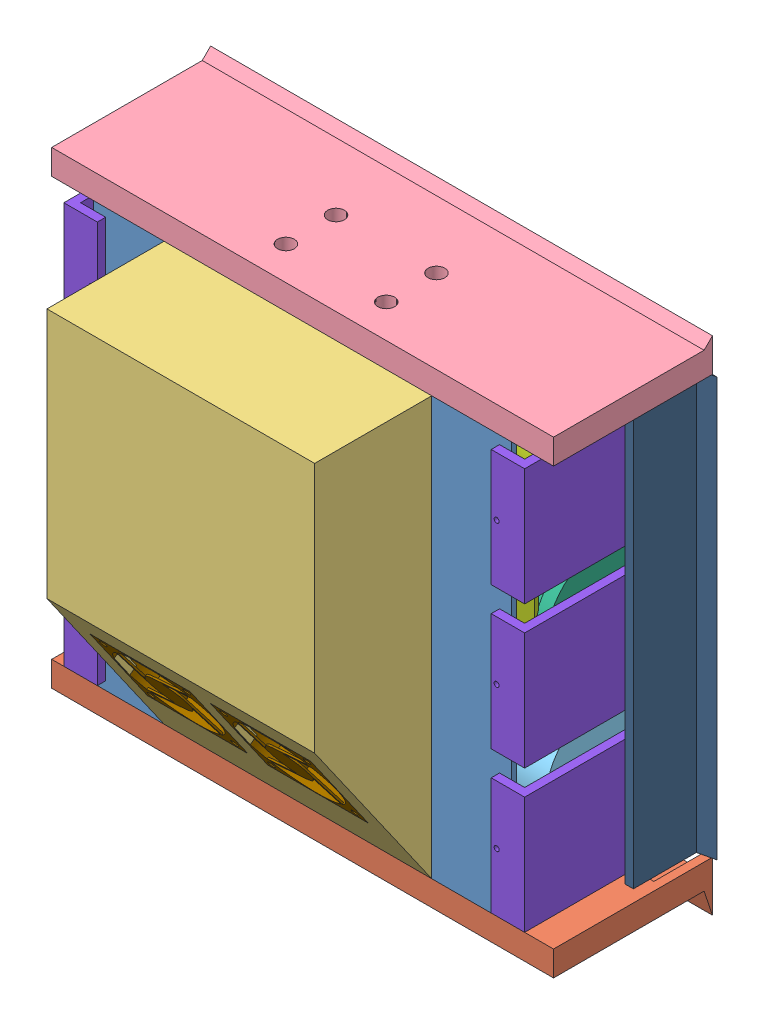
SolidWorks assembly Assemblage2, configuration Défaut. Lengths in mm.
Overall size (305.46 300 182.57).
24 component instances, 10 part files, 62 mates.
Components (placement in the parent):
- Pièce1-1: Pièce1 [Défaut] at (-19.0558 93.3364 250.0001) size (250 250 96)
- avant-1: avant [Défaut] at (151.0087 -127.6434 251.0001) x (-1 0 0) z (0 1 0) size (300 95 30)
- chassis sup-1: chassis sup [Défaut] at (-76.8076 137.3566 346.0001) x (0 1 0) z (1 0 0) size (250 70 160)
- arriere-1: arriere [Défaut] at (-148.9913 152.3566 251.0001) x (1 0 0) z (0 -1 0) size (300 95 20)
- roues 70x60-1: roues 70x60 [Défaut] at (116.0087 92.3566 280.5001) x (0 0.924225 0.381849) z (-1 0 0) size (70 70 60)
- roues 70x60-2: roues 70x60 [Défaut] at (56.0087 -67.6434 280.5001) x (0 0 -1) z (1 0 0) size (70 70 60)
- roues 70x60-3: roues 70x60 [Défaut] at (-53.9913 -67.6434 280.5001) x (0 0 1) z (-1 0 0) size (70 70 60)
- roues 70x60-4: roues 70x60 [Défaut] at (-113.9913 92.3566 280.5001) x (0 0 -1) z (1 0 0) size (70 70 60)
- roues moteur-1: roues moteur [Défaut] at (56.0087 12.3566 280.5001) x (0 0.453497 -0.891258) z (1 0 0) size (70 70 60)
- roues moteur-2: roues moteur [Défaut] at (-53.9913 12.3566 280.5001) x (0 -0.924225 -0.381849) z (-1 0 0) size (70 70 60)
- courroie-1: courroie [Défaut] at (89.0087 12.3566 280.5001) x (0 1 0) z (1 0 0) size (150 70 20)
- courroie-2: courroie [Défaut] at (63.0087 12.3566 280.5001) x (0 -1 0) z (1 0 0) size (150 70 20)
- courroie-3: courroie [Défaut] at (-80.9913 12.3566 280.5001) x (0 -1 0) z (1 0 0) size (150 70 20)
- courroie-4: courroie [Défaut] at (-106.4913 92.3566 280.5001) x (0 -1 0) z (1 0 0) size (150 70 20)
- Pièce6-2: Pièce6 [Défaut] at (118.7412 -37.6434 351.0001) x (0 1 0) z (0 0 -1) size (70 20 75)
- Pièce6-3: Pièce6 [Défaut] at (118.7412 47.3566 351.0001) x (0 1 0) z (0 0 -1) size (70 20 75)
- Pièce6-4: Pièce6 [Défaut] at (118.7412 132.3566 351.0001) x (0 1 0) z (0 0 -1) size (70 20 75)
- Pièce6-5: Pièce6 [Défaut] at (-116.7237 -107.6434 351.0001) x (0 -1 0) z (0 0 -1) size (70 20 75)
- Pièce6-6: Pièce6 [Défaut] at (-116.7237 -22.6434 351.0001) x (0 -1 0) z (0 0 -1) size (70 20 75)
- Pièce6-7: Pièce6 [Défaut] at (-116.7237 62.3566 351.0001) x (0 -1 0) z (0 0 -1) size (70 20 75)
- VENTILATEUR SUNON 60x60x25-1: VENTILATEUR SUNON 60x60x25 [Défaut] at (-38.8076 -55.2972 386.1425) x (1 0 0) z (0 -0.573462 0.819232) size (60 60 25)
- VENTILATEUR SUNON 60x60x25-2: VENTILATEUR SUNON 60x60x25 [Défaut] at (33.1924 -55.2972 386.1425) x (1 0 0) z (0 -0.573462 0.819232) size (60 60 25)
- cote-1: cote [Défaut] at (143.7412 137.3566 251.0001) x (0 -1 0) z (-1 0 0) size (250 40 15)
- cote-2: cote [Défaut] at (-141.7237 -112.6434 251.0001) x (0 1 0) z (1 0 0) size (250 40 15)
Mates (geometry in assembly coordinates):
- Coïncidente2: coincident aligned: plane of Pièce1-1 through (-19.0558 93.3364 346.0001) normal (0 0 1); plane of avant-1 through (151.0087 -122.6434 346.0001) normal (0 0 1)
- Coïncidente3: coincident anti-aligned: plane of Pièce1-1 through (-19.0558 93.3364 346.0001) normal (0 0 1); plane of chassis sup-1 through (73.1924 -112.6434 346.0001) normal (0 0 -1)
- Coïncidente4: coincident anti-aligned: line of Pièce1-1 through (-123.9913 -112.6434 346.0001) axis (1 0 0); line of chassis sup-1 through (78.1924 -112.6434 346.0001) axis (-1 0 0)
- Coïncidente5: coincident anti-aligned: plane of Pièce1-1 through (-43.9913 -112.6434 253.0001) normal (0 -1 0); plane of avant-1 through (151.0087 -112.6434 251.0001) normal (0 1 0)
- Distance1: distance = 25 mm aligned: plane of avant-1 through (151.0087 -122.6434 251.0001) normal (1 0 0); plane of Pièce1-1 through (126.0087 137.3566 346.0001) normal (1 0 0)
- Coïncidente7: coincident anti-aligned: plane of Pièce1-1 through (-43.9913 137.3566 253.0001) normal (0 1 0); plane of arriere-1 through (-148.9913 137.3566 251.0001) normal (0 -1 0)
- Distance2: distance = 25 mm aligned: plane of arriere-1 through (151.0087 147.3566 251.0001) normal (1 0 0); plane of Pièce1-1 through (126.0087 137.3566 346.0001) normal (1 0 0)
- Coïncidente9: coincident aligned: plane of Pièce1-1 through (-19.0558 93.3364 346.0001) normal (0 0 1); plane of arriere-1 through (-148.9913 147.3566 346.0001) normal (0 0 1)
- Coaxiale3: concentric aligned: cylinder of Pièce1-1 through (-40.9913 92.3566 280.5001) axis (-1 0 0) radius 2; cylinder of roues 70x60-4 through (-106.9913 92.3566 280.5001) axis (-1 0 0) radius 10
- Coaxiale4: concentric anti-aligned: cylinder of Pièce1-1 through (-40.9913 -67.6434 280.5001) axis (-1 0 0) radius 2.5; cylinder of roues 70x60-3 through (-60.9913 -67.6434 280.5001) axis (1 0 0) radius 10
- Coaxiale5: concentric anti-aligned: cylinder of Pièce1-1 through (43.0087 -67.6434 280.5001) axis (1 0 0) radius 2.5; cylinder of roues 70x60-2 through (63.0087 -67.6434 280.5001) axis (-1 0 0) radius 10
- Coaxiale7: concentric aligned: cylinder of Pièce1-1 through (43.0087 92.3566 280.5001) axis (1 0 0) radius 2; cylinder of roues 70x60-1 through (109.0087 92.3566 280.5001) axis (1 0 0) radius 10
- Distance3: distance = 10 mm anti-aligned: plane of roues 70x60-2 through (56.0087 -67.6434 280.5001) normal (-1 0 0); plane of Pièce1-1 through (46.0087 137.3566 253.0001) normal (1 0 0)
- Distance4: distance = 10 mm anti-aligned: plane of roues 70x60-1 through (56.0087 92.3566 280.5001) normal (-1 0 0); plane of Pièce1-1 through (46.0087 137.3566 253.0001) normal (1 0 0)
- Distance5: distance = 10 mm anti-aligned: plane of roues 70x60-3 through (-53.9913 -67.6434 280.5001) normal (1 0 0); plane of Pièce1-1 through (-43.9913 137.3566 253.0001) normal (-1 0 0)
- Distance6: distance = 10 mm anti-aligned: plane of Pièce1-1 through (-43.9913 137.3566 253.0001) normal (-1 0 0); plane of roues 70x60-4 through (-53.9913 92.3566 280.5001) normal (1 0 0)
- Coaxiale8: concentric anti-aligned: cylinder of Pièce1-1 through (43.0087 12.3566 280.5001) axis (1 0 0) radius 10; cylinder of roues moteur-1 through (63.5087 12.3566 280.5001) axis (-1 0 0) radius 10
- Distance8: distance = 10 mm anti-aligned: plane of Pièce1-1 through (46.0087 137.3566 253.0001) normal (1 0 0); plane of roues moteur-1 through (56.0087 12.3566 280.5001) normal (-1 0 0)
- Distance9: distance = 10 mm anti-aligned: plane of roues moteur-2 through (-53.9913 12.3566 280.5001) normal (1 0 0); plane of Pièce1-1 through (-43.9913 137.3566 253.0001) normal (-1 0 0)
- Coaxiale9: concentric anti-aligned: cylinder of Pièce1-1 through (-40.9913 12.3566 280.5001) axis (-1 0 0) radius 10; cylinder of roues moteur-2 through (-61.4913 12.3566 280.5001) axis (1 0 0) radius 10
- Coaxiale10: concentric anti-aligned: cylinder of roues 70x60-1 through (89.0087 92.3566 280.5001) axis (1 0 0) radius 32.5; cylinder of courroie-1 through (109.0087 92.3566 280.5001) axis (-1 0 0) radius 32.5
- Coaxiale13: concentric aligned: cylinder of roues moteur-1 through (108.5087 12.3566 280.5001) axis (-1 0 0) radius 32.5; cylinder of courroie-1 through (109.0087 12.3566 280.5001) axis (-1 0 0) radius 32.5
- Coïncidente18: coincident anti-aligned: plane of roues 70x60-1 through (89.0087 92.3566 280.5001) normal (1 0 0); plane of courroie-1 through (89.0087 12.3566 280.5001) normal (-1 0 0)
- Coïncidente19: coincident anti-aligned: plane of roues 70x60-2 through (63.0087 -67.6434 280.5001) normal (1 0 0); plane of courroie-2 through (63.0087 12.3566 280.5001) normal (-1 0 0)
- Coaxiale14: concentric aligned: cylinder of roues 70x60-2 through (83.0087 -67.6434 280.5001) axis (-1 0 0) radius 32.5; cylinder of courroie-2 through (83.0087 -67.6434 280.5001) axis (-1 0 0) radius 32.5
- Coaxiale15: concentric aligned: cylinder of roues moteur-1 through (83.5087 12.3566 280.5001) axis (-1 0 0) radius 32.5; cylinder of courroie-2 through (83.0087 12.3566 280.5001) axis (-1 0 0) radius 32.5
- Coaxiale16: concentric anti-aligned: cylinder of roues moteur-2 through (-106.4913 12.3566 280.5001) axis (1 0 0) radius 32.5; cylinder of courroie-4 through (-86.4913 12.3566 280.5001) axis (-1 0 0) radius 32.5
- Coïncidente20: coincident anti-aligned: plane of roues moteur-2 through (-86.4913 12.3566 280.5001) normal (-1 0 0); plane of courroie-4 through (-86.4913 92.3566 280.5001) normal (1 0 0)
- Coaxiale17: concentric aligned: cylinder of roues 70x60-4 through (-86.9913 92.3566 280.5001) axis (-1 0 0) radius 32.5; cylinder of courroie-4 through (-86.4913 92.3566 280.5001) axis (-1 0 0) radius 32.5
- Coaxiale18: concentric anti-aligned: cylinder of roues 70x60-3 through (-80.9913 -67.6434 280.5001) axis (1 0 0) radius 32.5; cylinder of courroie-3 through (-60.9913 -67.6434 280.5001) axis (-1 0 0) radius 32.5
- Coïncidente21: coincident anti-aligned: plane of roues 70x60-3 through (-60.9913 -67.6434 280.5001) normal (-1 0 0); plane of courroie-3 through (-60.9913 12.3566 280.5001) normal (1 0 0)
- Coaxiale19: concentric anti-aligned: cylinder of roues moteur-2 through (-81.4913 12.3566 280.5001) axis (1 0 0) radius 32.5; cylinder of courroie-3 through (-60.9913 12.3566 280.5001) axis (-1 0 0) radius 32.5
- Coaxiale20: concentric aligned: cylinder of Pièce1-1 through (122.0087 -72.6434 343.0001) axis (0 0 1) radius 1.5; cylinder of Pièce6-2 through (122.0087 -72.6434 291.0001) axis (0 0 1) radius 1.5
- Coïncidente22: coincident anti-aligned: plane of Pièce1-1 through (-19.0558 93.3364 346.0001) normal (0 0 1); plane of Pièce6-2 through (118.7412 -37.6434 346.0001) normal (0 0 -1)
- Parallèle1: parallel anti-aligned: plane of roues 70x60-2 through (116.0087 -67.6434 280.5001) normal (1 0 0); plane of Pièce6-2 through (133.7412 -107.6434 276.0001) normal (-1 0 0)
- Coïncidente24: coincident anti-aligned: plane of Pièce1-1 through (-19.0558 93.3364 346.0001) normal (0 0 1); plane of Pièce6-3 through (118.7412 47.3566 346.0001) normal (0 0 -1)
- Coaxiale21: concentric aligned: cylinder of Pièce1-1 through (122.0087 12.3566 343.0001) axis (0 0 1) radius 1.5; cylinder of Pièce6-3 through (122.0087 12.3566 291.0001) axis (0 0 1) radius 1.5
- Parallèle2: parallel anti-aligned: plane of roues moteur-1 through (116.0087 12.3566 280.5001) normal (1 0 0); plane of Pièce6-3 through (133.7412 -22.6434 276.0001) normal (-1 0 0)
- Coïncidente26: coincident anti-aligned: plane of Pièce1-1 through (-19.0558 93.3364 346.0001) normal (0 0 1); plane of Pièce6-4 through (118.7412 132.3566 346.0001) normal (0 0 -1)
- Coaxiale22: concentric aligned: cylinder of Pièce1-1 through (122.0087 97.3566 343.0001) axis (0 0 1) radius 1.5; cylinder of Pièce6-4 through (122.0087 97.3566 291.0001) axis (0 0 1) radius 1.5
- Parallèle3: parallel anti-aligned: plane of roues 70x60-1 through (116.0087 92.3566 280.5001) normal (1 0 0); plane of Pièce6-4 through (133.7412 62.3566 276.0001) normal (-1 0 0)
- Coïncidente28: coincident anti-aligned: plane of Pièce1-1 through (-19.0558 93.3364 346.0001) normal (0 0 1); plane of Pièce6-6 through (-116.7237 -22.6434 346.0001) normal (0 0 -1)
- Coaxiale23: concentric aligned: cylinder of Pièce1-1 through (-119.9913 12.3566 343.0001) axis (0 0 1) radius 1.5; cylinder of Pièce6-6 through (-119.9913 12.3566 291.0001) axis (0 0 1) radius 1.5
- Parallèle4: parallel anti-aligned: plane of roues moteur-2 through (-113.9913 12.3566 280.5001) normal (-1 0 0); plane of Pièce6-6 through (-131.7237 47.3566 276.0001) normal (1 0 0)
- Coïncidente30: coincident anti-aligned: plane of Pièce1-1 through (-19.0558 93.3364 346.0001) normal (0 0 1); plane of Pièce6-5 through (-116.7237 -107.6434 346.0001) normal (0 0 -1)
- Coaxiale24: concentric aligned: cylinder of Pièce1-1 through (-119.9913 -72.6434 343.0001) axis (0 0 1) radius 1.5; cylinder of Pièce6-5 through (-119.9913 -72.6434 291.0001) axis (0 0 1) radius 1.5
- Parallèle5: parallel anti-aligned: plane of roues 70x60-3 through (-113.9913 -67.6434 280.5001) normal (-1 0 0); plane of Pièce6-5 through (-131.7237 -37.6434 276.0001) normal (1 0 0)
- Coaxiale25: concentric aligned: cylinder of Pièce1-1 through (-119.9913 97.3566 343.0001) axis (0 0 1) radius 1.5; cylinder of Pièce6-7 through (-119.9913 97.3566 291.0001) axis (0 0 1) radius 1.5
- Parallèle6: parallel anti-aligned: plane of roues 70x60-4 through (-113.9913 92.3566 280.5001) normal (-1 0 0); plane of Pièce6-7 through (-131.7237 132.3566 276.0001) normal (1 0 0)
- Coïncidente36: coincident anti-aligned: plane of Pièce1-1 through (-19.0558 93.3364 346.0001) normal (0 0 1); plane of Pièce6-7 through (-116.7237 62.3566 346.0001) normal (0 0 -1)
- Coïncidente37: coincident aligned: plane of chassis sup-1 through (73.1924 -12.6434 416.0001) normal (0 -0.573462 0.819232); plane of VENTILATEUR SUNON 60x60x25-2 through (63.1924 -79.8741 368.9386) normal (0 -0.573462 0.819232)
- Coïncidente38: coincident aligned: plane of chassis sup-1 through (73.1924 -12.6434 416.0001) normal (0 -0.573462 0.819232); plane of VENTILATEUR SUNON 60x60x25-1 through (-8.8076 -79.8741 368.9386) normal (0 -0.573462 0.819232)
- Coïncidente39: coincident anti-aligned: plane of chassis sup-1 through (-8.8076 -26.6241 394.0071) normal (-1 0 0); plane of VENTILATEUR SUNON 60x60x25-1 through (-8.8076 -28.9998 400.8886) normal (1 0 0)
- Coïncidente40: coincident anti-aligned: plane of chassis sup-1 through (-66.8076 -74.1395 360.7463) normal (0 0.819232 0.573462); plane of VENTILATEUR SUNON 60x60x25-1 through (-68.8076 -78.1537 366.4809) normal (0 -0.819232 -0.573462)
- Coïncidente41: coincident anti-aligned: plane of chassis sup-1 through (63.1924 -74.1395 360.7463) normal (-1 0 0); plane of VENTILATEUR SUNON 60x60x25-2 through (63.1924 -28.9998 400.8886) normal (1 0 0)
- Coïncidente42: coincident anti-aligned: plane of chassis sup-1 through (5.1924 -74.1395 360.7463) normal (0 0.819232 0.573462); plane of VENTILATEUR SUNON 60x60x25-2 through (3.1924 -78.1537 366.4809) normal (0 -0.819232 -0.573462)
- Coïncidente43: coincident anti-aligned: plane of Pièce6-3 through (138.7412 47.3566 346.0001) normal (1 0 0); plane of cote-1 through (138.7412 137.3566 251.0001) normal (-1 0 0)
- Coïncidente44: coincident aligned: plane of avant-1 through (151.0087 -122.6434 251.0001) normal (0 0 -1); plane of cote-1 through (138.7412 137.3566 251.0001) normal (0 0 -1)
- Coïncidente45: coincident anti-aligned: plane of arriere-1 through (-148.9913 137.3566 251.0001) normal (0 -1 0); plane of cote-1 through (138.7412 137.3566 251.0001) normal (0 1 0)
- Coïncidente46: coincident anti-aligned: plane of Pièce6-6 through (-136.7237 -22.6434 346.0001) normal (-1 0 0); plane of cote-2 through (-136.7237 -112.6434 251.0001) normal (1 0 0)
- Coïncidente48: coincident aligned: plane of avant-1 through (151.0087 -122.6434 251.0001) normal (0 0 -1); plane of cote-2 through (-136.7237 -112.6434 251.0001) normal (0 0 -1)
- Coïncidente49: coincident anti-aligned: plane of avant-1 through (151.0087 -112.6434 251.0001) normal (0 1 0); plane of cote-2 through (-136.7237 -112.6434 251.0001) normal (0 -1 0)
